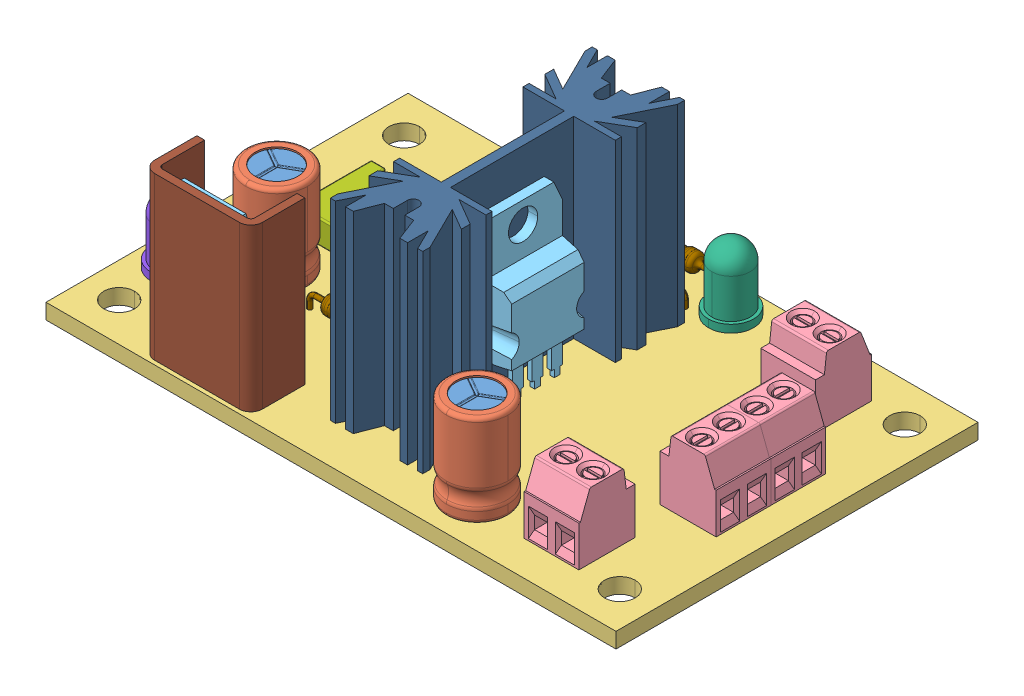
SolidWorks assembly CCM6N PWM DC 6V 12V 24V 6A Motor Speed Kontroller, configuration Default. Lengths in mm.
Overall size (74 29 47).
26 component instances, 11 part files, 0 mates.
Components (placement in the parent):
- CCM6N PWM DC 6V 12V 24V 6A Motor Speed Kontroller.STEP-1: CCM6N PWM DC 6V 12V 24V 6A Motor Speed Kontroller.STEP [Default] at origin size (74 29 47)
  - 100 uF Capacitor - Assmebly.STEP-1: 100 uF Capacitor - Assmebly.STEP [Default] at (-7.4697 -12.6976 8.4861) size (8.72 12 8)
    - 100 uF Capacitor - Capacitor.STEP-1: 100 uF Capacitor - Capacitor.STEP [Default] at origin size (8.72 11.61 7.64)
    - 100 uF Capacitor - Plastic Outer.STEP-1: 100 uF Capacitor - Plastic Outer.STEP [Default] at origin size (8 12 8)
  - 100 uF Capacitor - Assmebly.STEP-2: 100 uF Capacitor - Assmebly.STEP [Default] at (31.2639 -12.6976 21.1787) size (8.72 12 8)
    - 100 uF Capacitor - Capacitor.STEP-1: 100 uF Capacitor - Capacitor.STEP [Default] at origin size (8.72 11.61 7.64)
    - 100 uF Capacitor - Plastic Outer.STEP-1: 100 uF Capacitor - Plastic Outer.STEP [Default] at origin size (8 12 8)
  - CCM6N.STEP-1: CCM6N.STEP [Default] at (18.285 -20.4976 3.6751) size (74 2 47)
  - molex 2x.STEP-1: molex 2x.STEP [Default] at (42.4193 -18.4976 19.0364) x (-1 0 0) z (0 0 -1) size (7.11 12.01 7.29)
  - molex 2x.STEP-2: molex 2x.STEP [Default] at (42.4199 -18.4976 -11.6863) size (7.11 12.01 7.29)
  - molex 2x.STEP-3: molex 2x.STEP [Default] at (47.5374 -18.4976 -0.6028) x (0 0 1) z (-1 0 0) size (7.11 12.01 7.29)
  - molex 2x.STEP-4: molex 2x.STEP [Default] at (47.5374 -18.4976 6.5092) x (0 0 1) z (-1 0 0) size (7.11 12.01 7.29)
  - power_transistor.STEP-1: power_transistor.STEP [Default] at (0.4515 -13.8458 25.6552) x (-1 0 0) z (0 0 -1) size (10.2 22.85 4.5)
  - led orjinal_Varsayilan.STEP-1: led orjinal_Varsayilan.STEP [Default] at (9.5872 -17.4976 -15.8742) x (0 0 1) z (0 1 0) size (5.85 5.71 12.09)
  - led orjinal_Varsayilan.STEP-2: led orjinal_Varsayilan.STEP [Default] at (27.1694 -17.4976 -15.8742) x (0 0 1) z (0 1 0) size (5.85 5.71 12.09)
  - NE555.STEP-1: NE555.STEP [Default] at (-18.5825 -34.4247 202.7442) x (0 0 1) z (-1 0 0) size (9.94 7.05 8.79)
  - power_transistor.STEP-2: power_transistor.STEP [Default] at (19.623 -13.8458 4.8448) x (0 0 -1) z (1 0 0) size (10.2 22.85 4.5)
  - led orjinal green_Varsayilan.STEP-1: led orjinal green_Varsayilan.STEP [Default] at (-14.3393 -17.4976 15.0439) x (0 0 -1) z (0 1 0) size (5.85 5.71 12.09)
  - 1ko.STEP-1: 1ko.STEP [Default] at (-0.9134 -20.5136 8.7143) size (10.77 6.92 2.31)
  - 1ko.STEP-2: 1ko.STEP [Default] at (-0.9134 -20.5136 4.7143) size (10.77 6.92 2.31)
  - 1ko.STEP-3: 1ko.STEP [Default] at (-0.9134 -20.5136 0.7143) size (10.77 6.92 2.31)
  - 1ko.STEP-4: 1ko.STEP [Default] at (-0.9134 -20.5136 -3.2857) size (10.77 6.92 2.31)
  - 1ko.STEP-5: 1ko.STEP [Default] at (13.2086 -20.5136 -19.7037) size (10.77 6.92 2.31)
  - 1ko.STEP-6: 1ko.STEP [Default] at (13.2086 -20.5136 -15.7037) size (10.77 6.92 2.31)
  - heat sink.STEP-1: heat sink.STEP [Default] at (19.033 -18.4976 5.0063) x (0 0 1) z (-1 0 0) size (34 25 12)
  - het.STEP-1: het.STEP [Default] at (0.3515 -18.4976 25.6452) x (-1 0 0) z (0 0 -1) size (14 21 7)
